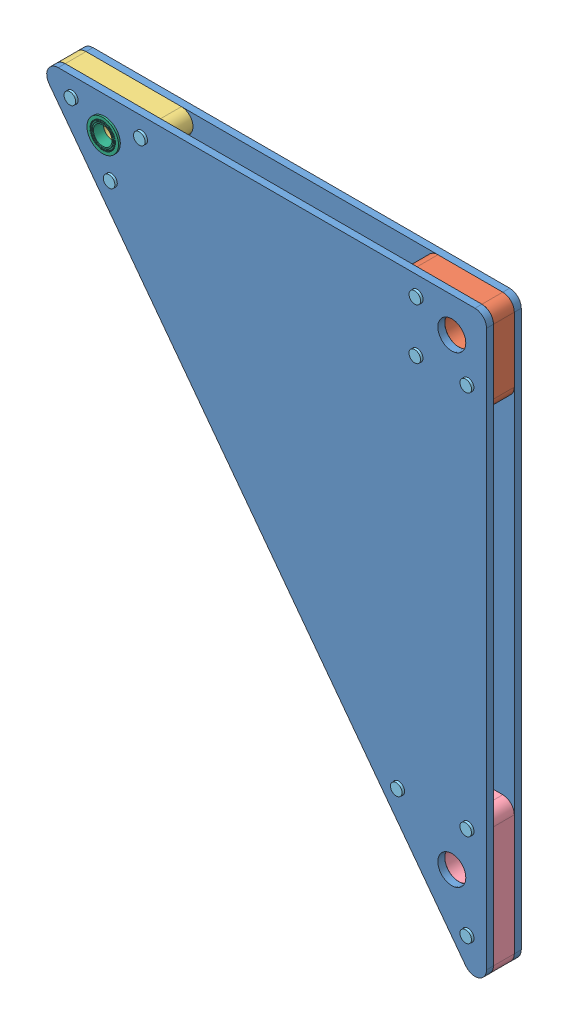
SolidWorks assembly 下方三脚架装配, configuration 默认. Lengths in mm.
Overall size (190 250 18.2).
16 component instances, 6 part files, 34 mates.
Components (placement in the parent):
- 下方三角架-1: 下方三角架 [默认] at (21.0882 99.8369 250) size (190 250 3)
- 下方三角架打印连接件1-1: 下方三角架打印连接件1 [默认] at (16.2485 93.6671 253) x (0 -1 0) z (0 0 1) size (38 38 9)
- 下方三角架打印连接件2-1: 下方三角架打印连接件2 [默认] at (-153.1088 87.5163 262) x (-1 0 0) z (0 0 -1) size (51.2 41.04 9)
- 下方三角架打印连接件3-1: 下方三角架打印连接件3 [默认] at (16.3598 -93.3236 262) x (-1 0 0) z (0 0 -1) size (49 62 9)
- 下方三角架-2: 下方三角架 [默认] at (21.0882 99.8369 262) size (190 250 3)
- flat head rivets gb-2: flat head rivets gb [GB_CONNECTING_PIECE_RIVET_FHRS 5X16] at (6.0882 106.8369 247.8) x (0 0 1) z (0.923728 0.383049 0) size (18.2 10.29 10.29)
- flat head rivets gb-3: flat head rivets gb [GB_CONNECTING_PIECE_RIVET_FHRS 5X16] at (6.0882 84.8369 247.8) x (0 0 1) z (0.923728 0.383049 0) size (18.2 10.29 10.29)
- flat head rivets gb-4: flat head rivets gb [GB_CONNECTING_PIECE_RIVET_FHRS 5X16] at (-1.9118 -81.1631 247.8) x (0 0 1) z (0.923728 0.383049 0) size (18.2 10.29 10.29)
- flat head rivets gb-5: flat head rivets gb [GB_CONNECTING_PIECE_RIVET_FHRS 5X16] at (28.0882 84.8369 247.8) x (0 0 1) z (0.923728 0.383049 0) size (18.2 10.29 10.29)
- flat head rivets gb-6: flat head rivets gb [GB_CONNECTING_PIECE_RIVET_FHRS 5X16] at (-142.9118 106.8369 247.8) x (0 0 1) z (-0.957579 0.288172 0) size (18.2 10.29 10.29)
- flat head rivets gb-7: flat head rivets gb [GB_CONNECTING_PIECE_RIVET_FHRS 5X16] at (-125.9607 84.2354 247.8) x (0 0 1) z (0.923728 0.383049 0) size (18.2 10.29 10.29)
- flat head rivets gb-8: flat head rivets gb [GB_CONNECTING_PIECE_RIVET_FHRS 5X16] at (-112.9118 106.8369 247.8) x (0 0 1) z (0.923728 0.383049 0) size (18.2 10.29 10.29)
- flat head rivets gb-9: flat head rivets gb [GB_CONNECTING_PIECE_RIVET_FHRS 5X16] at (28.0882 -81.1631 247.8) x (0 0 1) z (0.923728 0.383049 0) size (18.2 10.29 10.29)
- flat head rivets gb-10: flat head rivets gb [GB_CONNECTING_PIECE_RIVET_FHRS 5X16] at (28.0882 -121.1631 247.8) x (0 0 1) z (0.923728 0.383049 0) size (18.2 10.29 10.29)
- SFL678ZZ深沟球法兰杯轴承-3: SFL678ZZ深沟球法兰杯轴承 [默认] at (-128.9118 99.8369 263.6) x (0 0 1) z (-0.848722 0.528839 0) size (4.3 13.6 13.6)
- SFL678ZZ深沟球法兰杯轴承-4: SFL678ZZ深沟球法兰杯轴承 [默认] at (-128.9118 99.8369 251.4) x (0 0 -1) z (0.923728 0.383049 0) size (4.3 13.6 13.6)
Mates (geometry in assembly coordinates):
- 重合2: coincident: plane of 下方三角架-1 through (21.0882 99.8369 253) normal (0 0 1); plane of 下方三角架打印连接件1-1 through (16.2485 93.6671 253) normal (0 0 -1)
- 同心2: concentric: cylinder of 下方三角架-1 through (28.0882 84.8369 253) axis (0 0 -1) radius 2.55; cylinder of 下方三角架打印连接件1-1 through (28.0882 84.8369 262) axis (0 0 -1) radius 2.5
- 同心3: concentric: cylinder of 下方三角架-1 through (6.0882 106.8369 253) axis (0 0 -1) radius 2.6; cylinder of 下方三角架打印连接件1-1 through (6.0882 106.8369 262) axis (0 0 -1) radius 2.5
- 重合3: coincident: plane of 下方三角架-1 through (21.0882 99.8369 253) normal (0 0 1); plane of 下方三角架打印连接件3-1 through (16.3598 -93.3236 253) normal (0 0 -1)
- 同心4: concentric: cylinder of 下方三角架-1 through (28.0882 -121.1631 253) axis (0 0 -1) radius 2.6; cylinder of 下方三角架打印连接件3-1 through (28.0882 -121.1631 253) axis (0 0 1) radius 2.55
- 同心5: concentric: cylinder of 下方三角架-1 through (28.0882 -81.1631 253) axis (0 0 -1) radius 2.6; cylinder of 下方三角架打印连接件3-1 through (28.0882 -81.1631 253) axis (0 0 1) radius 2.55
- 重合4: coincident: plane of 下方三角架-1 through (21.0882 99.8369 253) normal (0 0 1); plane of 下方三角架打印连接件2-1 through (-153.1088 87.5163 253) normal (0 0 -1)
- 同心6: concentric: cylinder of 下方三角架-1 through (-125.9607 84.2354 253) axis (0 0 -1) radius 2.55; cylinder of 下方三角架打印连接件2-1 through (-125.9607 84.2354 253) axis (0 0 1) radius 2.55
- 同心7: concentric: cylinder of 下方三角架-1 through (-142.9118 106.8369 253) axis (0 0 -1) radius 2.55; cylinder of 下方三角架打印连接件2-1 through (-142.9118 106.8369 253) axis (0 0 1) radius 2.55
- 重合5: coincident: plane of 下方三角架打印连接件2-1 through (-153.1088 87.5163 262) normal (0 0 1); plane of 下方三角架-2 through (21.0882 99.8369 262) normal (0 0 -1)
- 同心8: concentric: cylinder of 下方三角架打印连接件1-1 through (21.0882 99.8369 262) axis (0 0 -1) radius 6; cylinder of 下方三角架-2 through (21.0882 99.8369 265) axis (0 0 -1) radius 6.05
- 同心9: concentric: cylinder of 下方三角架打印连接件2-1 through (-128.9118 99.8369 253) axis (0 0 1) radius 6; cylinder of 下方三角架-2 through (-128.9118 99.8369 265) axis (0 0 -1) radius 6.05
- 同心11: concentric: cylinder of 下方三角架打印连接件1-1 through (6.0882 106.8369 262) axis (0 0 -1) radius 2.5; cylinder of flat head rivets gb-2 through (6.0882 106.8369 245.4817) axis (0 0 -1) radius 2.5
- 重合7: coincident: plane of 下方三角架-1 through (21.0882 99.8369 250) normal (0 0 -1); plane of flat head rivets gb-2 through (8.0135 102.1942 250) normal (0 0 1)
- 同心12: concentric: cylinder of 下方三角架打印连接件1-1 through (6.0882 84.8369 262) axis (0 0 -1) radius 2.5; cylinder of flat head rivets gb-3 through (6.0882 84.8369 245.4817) axis (0 0 -1) radius 2.5
- 重合8: coincident: plane of 下方三角架-1 through (21.0882 99.8369 250) normal (0 0 -1); plane of flat head rivets gb-3 through (8.0135 80.1942 250) normal (0 0 1)
- 同心13: concentric: cylinder of 下方三角架打印连接件1-1 through (28.0882 84.8369 262) axis (0 0 -1) radius 2.5; cylinder of flat head rivets gb-5 through (28.0882 84.8369 245.4817) axis (0 0 -1) radius 2.5
- 重合9: coincident: plane of 下方三角架-1 through (21.0882 99.8369 250) normal (0 0 -1); plane of flat head rivets gb-5 through (30.0135 80.1942 250) normal (0 0 1)
- 同心14: concentric: cylinder of 下方三角架打印连接件2-1 through (-142.9118 106.8369 253) axis (0 0 1) radius 2.55; cylinder of flat head rivets gb-6 through (-142.9118 106.8369 245.4817) axis (0 0 -1) radius 2.5
- 重合10: coincident: plane of 下方三角架-1 through (21.0882 99.8369 250) normal (0 0 -1); plane of flat head rivets gb-6 through (-141.4634 111.6497 250) normal (0 0 1)
- 同心15: concentric: cylinder of 下方三角架-1 through (-125.9607 84.2354 253) axis (0 0 -1) radius 2.55; cylinder of flat head rivets gb-7 through (-125.9607 84.2354 245.4817) axis (0 0 -1) radius 2.5
- 重合12: coincident: plane of 下方三角架-1 through (21.0882 99.8369 250) normal (0 0 -1); plane of flat head rivets gb-7 through (-124.0355 79.5928 250) normal (0 0 1)
- 同心16: concentric: cylinder of 下方三角架-1 through (-112.9118 106.8369 253) axis (0 0 -1) radius 2.55; cylinder of flat head rivets gb-8 through (-112.9118 106.8369 245.4817) axis (0 0 -1) radius 2.5
- 重合13: coincident: plane of 下方三角架-1 through (21.0882 99.8369 250) normal (0 0 -1); plane of flat head rivets gb-8 through (-110.9865 102.1942 250) normal (0 0 1)
- 同心17: concentric: cylinder of 下方三角架-1 through (-1.9118 -81.1631 253) axis (0 0 -1) radius 2.6; cylinder of flat head rivets gb-4 through (-1.9118 -81.1631 245.4817) axis (0 0 -1) radius 2.5
- 重合14: coincident: plane of 下方三角架-1 through (21.0882 99.8369 250) normal (0 0 -1); plane of flat head rivets gb-4 through (0.0135 -85.8058 250) normal (0 0 1)
- 同心18: concentric: cylinder of 下方三角架-1 through (28.0882 -81.1631 253) axis (0 0 -1) radius 2.6; cylinder of flat head rivets gb-9 through (28.0882 -81.1631 245.4817) axis (0 0 -1) radius 2.5
- 重合15: coincident: plane of 下方三角架-1 through (21.0882 99.8369 250) normal (0 0 -1); circle of flat head rivets gb-9
- 同心19: concentric: cylinder of 下方三角架-1 through (28.0882 -121.1631 253) axis (0 0 -1) radius 2.6; cylinder of flat head rivets gb-10 through (28.0882 -121.1631 245.4817) axis (0 0 -1) radius 2.5
- 重合16: coincident: plane of 下方三角架-1 through (21.0882 99.8369 250) normal (0 0 -1); plane of flat head rivets gb-10 through (30.0135 -125.8058 250) normal (0 0 1)
- 同心22: concentric: cylinder of 下方三角架打印连接件2-1 through (-128.9118 99.8369 253) axis (0 0 1) radius 6; cylinder of SFL678ZZ深沟球法兰杯轴承-4 through (-128.9118 99.8369 258.3125) axis (0 0 1) radius 6
- 重合19: coincident: plane of 下方三角架-1 through (21.0882 99.8369 250) normal (0 0 -1); plane of SFL678ZZ深沟球法兰杯轴承-4 through (-131.5165 106.1182 250) normal (0 0 1)
- 同心23: concentric: cylinder of 下方三角架打印连接件2-1 through (-128.9118 99.8369 253) axis (0 0 1) radius 6; cylinder of SFL678ZZ深沟球法兰杯轴承-3 through (-128.9118 99.8369 256.6875) axis (0 0 -1) radius 6
- 重合20: coincident: plane of 下方三角架-2 through (21.0882 99.8369 265) normal (0 0 1); plane of SFL678ZZ深沟球法兰杯轴承-3 through (-125.3157 105.6082 265) normal (0 0 -1)
